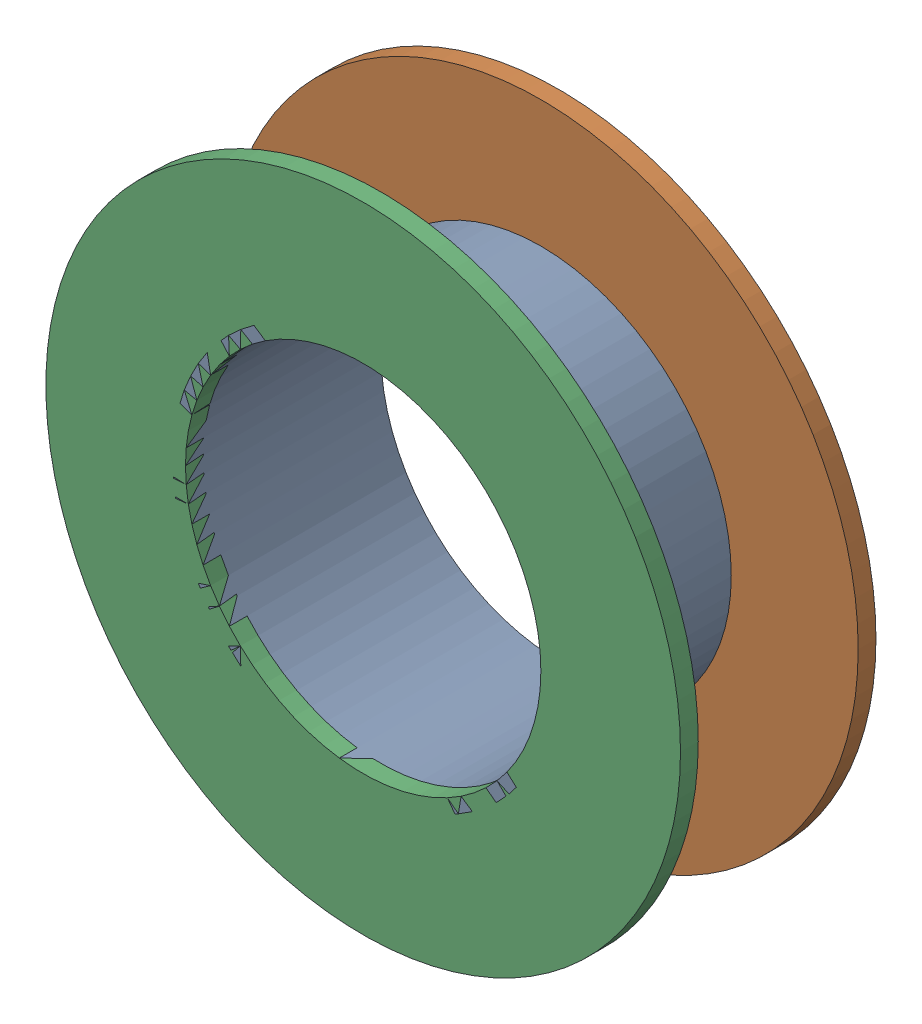
SolidWorks assembly Via (21.9mm,40mm) from Top Layer to Bottom Layer, configuration Predeterminado. Lengths in mm.
Overall size (1.27 1.27 0.39).
6 component instances, 2 part files, 0 mates.
Components (placement in the parent):
- Via Hole-1: Via Hole [Predeterminado] at (21.9 40 -0.4013) size (0.76 0.76 0.39)
  - Via Hole-Part-1-1: Via Hole-Part-1 [Predeterminado] at origin size (0.76 0.76 0.39)
- Via Top Layer-1: Via Top Layer [Predeterminado] at (21.9 40 -0.4013) size (1.27 1.27 0.04)
  - Via Top Layer-Part-1-1: Via Top Layer-Part-1 [Predeterminado] at origin size (1.27 1.27 0.04)
- Via Top Layer-2: Via Top Layer [Predeterminado] at (21.9 40 -0.0457) size (1.27 1.27 0.04)
  - Via Top Layer-Part-1-1: Via Top Layer-Part-1 [Predeterminado] at origin size (1.27 1.27 0.04)
